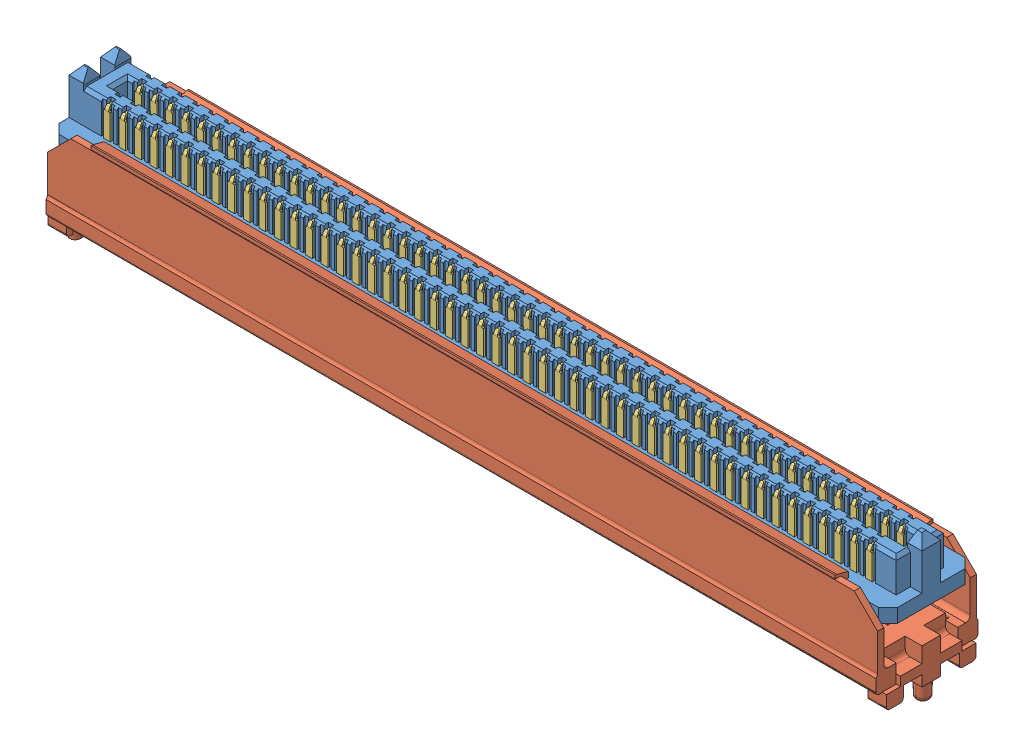
SolidWorks assembly Assem4, configuration Default. Lengths in mm.
Overall size (68.48 11.86 8.33).
6 component instances, 5 part files, 3 mates.
Components (placement in the parent):
- SEAM_50_07_0_L_04_2_A_K_TR-1: SEAM_50_07_0_L_04_2_A_K_TR [Default] at (0 6.8834 0) size (68.48 11.86 8.33)
  - _SEAM_50_07_0_L_04_1_A_K_TR_body_2-1: _SEAM_50_07_0_L_04_1_A_K_TR_body_2 [Default] at origin size (68.48 6.35 7.06)
  - _SEAM_50_07_0_L_04_1_A_K_TR_spacer_4-1: _SEAM_50_07_0_L_04_1_A_K_TR_spacer_4 [Default] at origin size (68.48 9.12 8.33)
  - _SEAM_50_07_0_L_04_1_A_K_TR_conn_6-1: _SEAM_50_07_0_L_04_1_A_K_TR_conn_6 [Default] at origin size (67.97 9.28 6.55)
  - _SEAM_K_Pad_04_8-1: _SEAM_K_Pad_04_8 [Default] at (0 2.6924 0) size (5.99 0.13 5.99) (hidden)
  - _SEAM_Triangle_10-1: _SEAM_Triangle_10 [Default] at (32.2834 1.2954 -1.6764) x (-1 0 0) z (0 0 -1) size (1.02 1.27 0.13)
Mates (geometry in assembly coordinates):
- Coincident1: coincident: plane of ? through (32.7152 0 3.4036) normal (0 -1 0)
- Coincident2: coincident: plane of ? through (0 6.8834 0) normal (1 0 0)
- Coincident3: coincident: plane of ? through (0 6.8834 0) normal (0 0 1)
